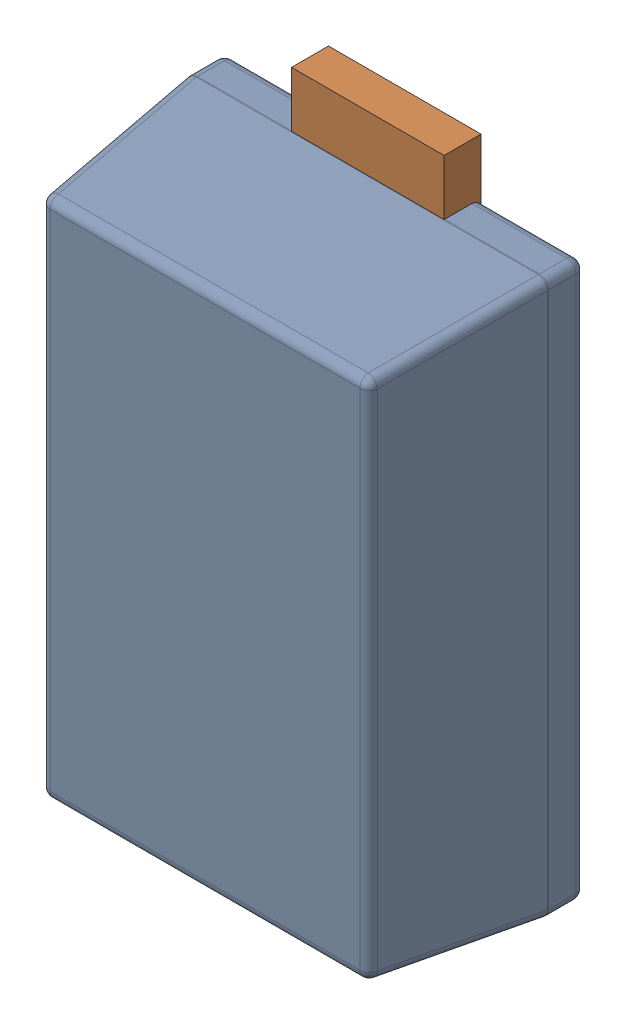
SolidWorks assembly D10, configuration Default. Lengths in mm.
Overall size (1.96 3.6 1.08).
5 component instances, 2 part files, 0 mates.
Components (placement in the parent):
- 809573488-1: 809573488 [Default] at (92.9653 33.147 0) x (0 -1 0) z (0 0 1) size (3.6 1.96 1.08)
  - Body_4-1: Body_4 [Default] at (-1.5 -0.975 0) size (3.01 1.96 1.08)
    - Open_CASCADE_STEP_translator_6.8_1.1.1_3-1: Open_CASCADE_STEP_translator_6.8_1.1.1_3 [Default] at origin size (3.01 1.96 1.08)
  - lead_3-1: lead_3 [Default] at (-1.8 -0.4125 0) size (0.68 0.82 0.2)
  - lead_3-2: lead_3 [Default] at (1.8 0.4125 0) x (-1 0 0) z (0 0 1) size (0.68 0.82 0.2)
